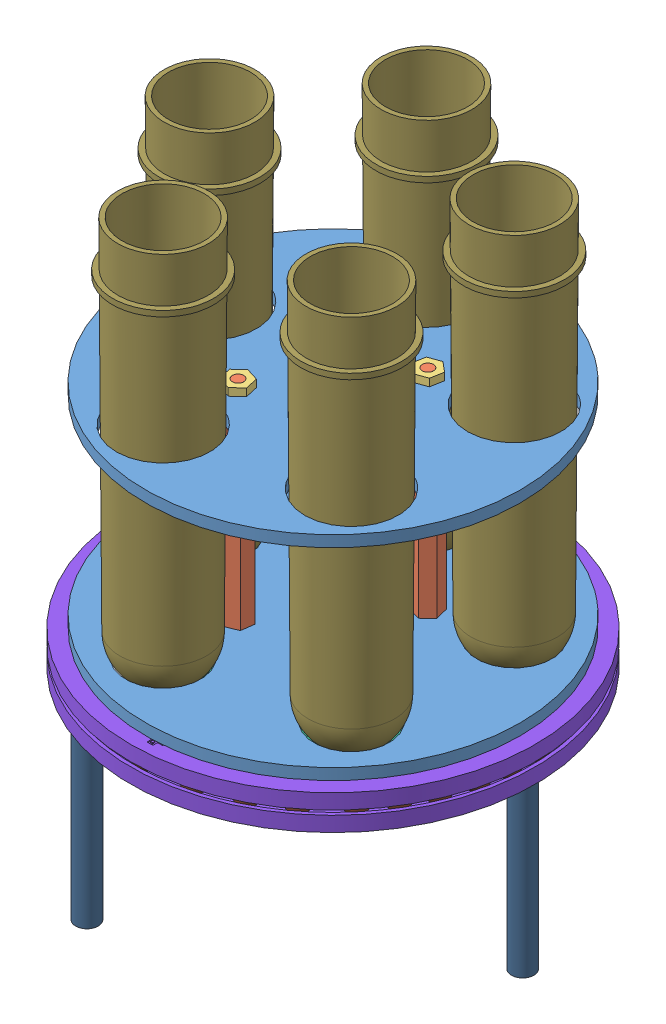
SolidWorks assembly FinalTurntable, configuration Default. Lengths in mm.
Overall size (140.72 159.12 140.72).
63 component instances, 12 part files, 80 mates.
Components (placement in the parent):
- RackTopBottom - Updated-1: RackTopBottom - Updated [Default] at (-230.4539 59.2001 -51.3207) x (-0.633158 0 0.774022) z (0 1 0) size (100 100 56.8)
- Hex Standoff - Updated-1: Hex Standoff - Updated [Default] at (-241.2075 5.7001 -16.3075) x (0.593372 0 -0.804928) z (0 1 0) size (6.07 6.93 56)
- Hex Standoff - Updated-2: Hex Standoff - Updated [Default] at (-234.6976 5.7001 -29.2259) x (0.991066 0 0.133372) z (0 1 0) size (6.07 6.93 56)
- Hex Standoff - Updated-3: Hex Standoff - Updated [Default] at (-210.597 5.7001 -45.9336) x (0.250303 0 -0.968168) z (0 1 0) size (6.07 6.93 56)
- Hex Standoff - Updated-4: Hex Standoff - Updated [Default] at (-265.0629 5.7001 -66.876) x (0.649234 0 0.760589) z (0 1 0) size (6.07 6.93 56)
- M3 Nut Standoff - Updated-1: M3 Nut Standoff - Updated [Default] at (-253.6241 66.7001 -101.6071) x (0.21848 0 0.975841) z (0 -1 0) size (6 6.93 2)
- M3 Nut Standoff - Updated-2: M3 Nut Standoff - Updated [Default] at (-253.226 66.7001 0.9306) x (0.296982 0 -0.954883) z (0 -1 0) size (6 6.93 2)
- M3 Nut Standoff - Updated-3: M3 Nut Standoff - Updated [Default] at (-244.486 66.7001 -34.4131) x (0.64612 0 -0.763236) z (0 -1 0) size (6 6.93 2)
- M3 Nut Standoff - Updated-4: M3 Nut Standoff - Updated [Default] at (-201.2406 66.7001 -76.8592) x (-0.394236 0 0.919009) z (0 -1 0) size (6 6.93 2)
- M3 Standoff Screw - Updated-1: M3 Standoff Screw - Updated [Default] at (-269.8082 0.4001 -37.3883) x (1 0 0) z (0 1 0) size (6 6 11.5)
- BottomPlate-2: BottomPlate [Default] at (-230.4539 2.9001 -51.3207) x (-0.774022 0 -0.633158) z (0 -1 0) size (48 48 1)
- M3 Standoff Screw - Updated-5: M3 Standoff Screw - Updated [Default] at (-244.479 0.4001 -39.9238) x (1 0 0) z (0 1 0) size (6 6 11.5)
- M3 Standoff Screw - Updated-6: M3 Standoff Screw - Updated [Default] at (-270.5567 0.4001 -52.8823) x (0.936079 0 -0.351791) z (0 1 0) size (6 6 11.5)
- M3 Standoff Screw - Updated-7: M3 Standoff Screw - Updated [Default] at (-247.0145 0.4001 -65.2531) x (1 0 0) z (0 1 0) size (6 6 11.5)
- 50T-1: 50T [Default] at (-230.4539 -13.5499 -51.3207) x (-0.99923 0 0.039234) z (0 1 0) size (52 51.94 5.85)
- M4x40 Screw - Updated-2: M4x40 Screw - Updated [Default] at (-230.4539 5.4001 -51.3207) x (0.031411 0 -0.999507) z (0 -1 0) size (7.8 7.8 42.5)
- OuterBearing-1: OuterBearing [Default] at (-230.4539 4.4001 -51.3207) x (0.998722 0 0.050545) z (-0.050545 0 0.998722) size (108 4 108)
- M4 Nut - Updated-4: M4 Nut - Updated [Default] at (-246.9134 -19.2999 -51.8372) x (1 0 -0.000085) z (0 1 0) size (7.12 8.08 3)
- OuterBearing-2: OuterBearing [Default] at (-230.4539 -2.7999 -51.3207) x (-0.031858 0 -0.999492) z (-0.999492 0 0.031858) size (108 4 108)
- Holder-5: Holder [Default] at (-249.9816 -48.7999 -5.2134) size (6 45 6)
- Holder-6: Holder [Default] at (-251.5763 -48.7999 -96.9017) size (6 45 6)
- Holder-7: Holder [Default] at (-180.5025 -48.7999 -51.9772) size (6 45 6)
- Plastic BB-15: Plastic BB [Default] at (-275.5002 13.1962 -61.2014) x (0.215326 -0.491343 0.843929) z (-0.86299 0.308718 0.399927) size (6 6 6)
- Plastic BB-16: Plastic BB [Default] at (-242.8287 -17.2199 -25.7204) size (6 6 6)
- Plastic BB-17: Plastic BB [Default] at (-256.14 -25.7464 43.5967) x (0.678924 0.269881 -0.682808) z (0.333731 0.71493 0.614409) size (6 6 6)
- Plastic BB-18: Plastic BB [Default] at (-247.5088 -17.2229 -19.1254) size (6 6 6)
- Plastic BB-19: Plastic BB [Default] at (-223.1694 -8.2487 -9.1728) x (0.880848 -0.040835 -0.471634) z (0.321981 0.782021 0.53364) size (6 6 6)
- Plastic BB-20: Plastic BB [Default] at (-332.3096 6.3553 -15.6932) x (0.865873 -0.39899 -0.30178) z (0.277856 -0.118075 0.953339) size (6 6 6)
- Plastic BB-21: Plastic BB [Default] at (-272.092 -55.586 -78.0495) x (0.162347 0.858831 -0.485853) z (0.986726 -0.143278 0.076444) size (6 6 6)
- Plastic BB-22: Plastic BB [Default] at (-293.3514 50.1494 -52.6083) x (0.09026 -0.963623 -0.251565) z (0.58268 -0.153756 0.798024) size (6 6 6)
- Plastic BB-23: Plastic BB [Default] at (-239.3384 -17.2401 -32.7624) size (6 6 6)
- Plastic BB-24: Plastic BB [Default] at (-233.1099 -29.6982 -80.7632) x (0.962684 0.242 0.12114) z (-0.073563 -0.196771 0.977686) size (6 6 6)
- Plastic BB-25: Plastic BB [Default] at (-236.9966 -17.2491 -62.344) size (6 6 6)
- Plastic BB-26: Plastic BB [Default] at (-252.809 -17.2534 -88.963) size (6 6 6)
- Plastic BB-27: Plastic BB [Default] at (-220.4475 52.4169 -122.4108) x (0.369836 -0.908472 0.19468) z (-0.706984 -0.411127 -0.575455) size (6 6 6)
- Plastic BB-28: Plastic BB [Default] at (-247.7003 -10.1249 -56.4794) x (0.84441 -0.082528 -0.529302) z (0.492353 0.508909 0.706116) size (6 6 6)
- Plastic BB-29: Plastic BB [Default] at (-235.9603 -17.2443 -55.6713) size (6 6 6)
- Plastic BB-30: Plastic BB [Default] at (-308.099 32.6865 6.1519) x (0.755938 -0.653121 -0.044618) z (0.636947 0.718053 0.280532) size (6 6 6)
- Plastic BB-31: Plastic BB [Default] at (-156.6909 -25.2421 -11.8489) x (-0.812463 0.549497 -0.194826) z (0.443508 0.799428 0.405235) size (6 6 6)
- Plastic BB-32: Plastic BB [Default] at (-252.0729 -24.2451 -53.1086) x (-0.025583 0.257835 0.96585) z (-0.604245 0.765707 -0.220412) size (6 6 6)
- Plastic BB-33: Plastic BB [Default] at (-253.0916 -3.1833 12.282) x (0.921672 -0.229863 -0.312544) z (0.37337 0.306604 0.875551) size (6 6 6)
- Plastic BB-34: Plastic BB [Default] at (-243.3801 -12.867 48.2726) x (0.609745 -0.007805 -0.792559) z (0.616623 0.632933 0.468158) size (6 6 6)
- Plastic BB-35: Plastic BB [Default] at (-229.7792 -39.1049 -66.1656) x (0.86679 0.431125 -0.250614) z (0.208293 0.143611 0.967466) size (6 6 6)
- Plastic BB-36: Plastic BB [Default] at (-233.4906 2.832 -14.1696) x (0.899081 -0.311551 -0.307555) z (0.422142 0.430869 0.797589) size (6 6 6)
- Plastic BB-37: Plastic BB [Default] at (-201.7036 53.4469 -110.7371) x (-0.579141 -0.734052 0.354631) z (0.634275 -0.132442 0.761679) size (6 6 6)
- Plastic BB-38: Plastic BB [Default] at (-333.4327 -9.8102 -21.447) x (0.984185 -0.078607 -0.158748) z (0.175493 0.554722 0.813318) size (6 6 6)
- Plastic BB-39: Plastic BB [Default] at (-233.1878 56.1453 -83.4812) x (-0.297194 -0.952912 -0.060283) z (0.721846 -0.265559 0.639075) size (6 6 6)
- Plastic BB-40: Plastic BB [Default] at (-227.3253 50.3183 -131.584) x (-0.072989 -0.646912 0.759063) z (0.997324 -0.050472 0.052885) size (6 6 6)
- Plastic BB-41: Plastic BB [Default] at (-212.2193 58.5346 -93.915) x (-0.063933 -0.974181 0.216526) z (0.995478 -0.077531 -0.054889) size (6 6 6)
- Plastic BB-42: Plastic BB [Default] at (-243.6939 24.8361 -129.5389) x (-0.681198 -0.243959 0.690256) z (0.285251 0.779885 0.557146) size (6 6 6)
- Plastic BB-43: Plastic BB [Default] at (-327.4625 -11.0441 -27.8578) x (0.870988 -0.102666 -0.480457) z (0.490227 0.246332 0.836061) size (6 6 6)
- Plastic BB-44: Plastic BB [Default] at (-302.7247 -13.2486 -16.1662) x (0.972922 -0.070587 0.220093) z (-0.218423 0.030653 0.975373) size (6 6 6)
- Plastic BB-45: Plastic BB [Default] at (-330.7628 -21.1236 -29.0992) x (0.954445 0.078409 -0.287901) z (0.262205 0.240139 0.934656) size (6 6 6)
- Plastic BB-46: Plastic BB [Default] at (-321.6598 -22.7683 -11.6677) x (0.98991 0.140708 0.016736) z (-0.082434 0.475788 0.875688) size (6 6 6)
- Plastic BB-47: Plastic BB [Default] at (-306.2301 17.5255 -81.6087) x (0.830622 -0.547854 -0.099614) z (0.34971 0.374028 0.858957) size (6 6 6)
- Plastic BB-48: Plastic BB [Default] at (-227.852 -23.7397 -50.0655) x (-0.965187 0.239718 -0.104641) z (-0.112351 -0.741238 -0.661773) size (6 6 6)
- Plastic BB-49: Plastic BB [Default] at (-296.4909 -33.9533 15.134) x (0.571556 0.340695 -0.746492) z (0.671919 0.32787 0.664098) size (6 6 6)
- Plastic BB-50: Plastic BB [Default] at (-269.7873 53.6028 -93.5405) x (0.120309 -0.992302 -0.029353) z (0.208526 -0.003648 0.97801) size (6 6 6)
- TestTube-1: TestTube [Default] at (-201.0065 2.8659 -70.2375) x (-0.772425 0 -0.635106) z (0 1 0) size (27 27 107)
- TestTube-2: TestTube [Default] at (-265.3965 2.7959 -53.3254) x (-0.855611 0 -0.517619) z (0 1 0) size (27 27 107)
- TestTube-3: TestTube [Default] at (-243.1584 3.1689 -18.7078) x (-0.945003 0 -0.327061) z (0 1 0) size (27 27 107)
- TestTube-4: TestTube [Default] at (-203.3632 3.3236 -29.1601) x (-0.627624 0 -0.778516) z (0 1 0) size (27 27 107)
- TestTube-5: TestTube [Default] at (-239.3452 2.8224 -85.1725) x (-0.793467 0 -0.608613) z (0 1 0) size (27 27 107)
Mates (geometry in assembly coordinates):
- Concentric5: concentric aligned: cylinder of RackTopBottom - Updated-1 through (-216.5215 59.2001 -39.9238) axis (0 1 0) radius 1.5; cylinder of Hex Standoff - Updated-2 through (-216.5215 8.2001 -39.9238) axis (0 1 0) radius 1.5
- Coincident2: coincident anti-aligned: plane of RackTopBottom - Updated-1 through (-230.4539 59.2001 -51.3207) normal (0 -1 0); plane of Hex Standoff - Updated-2 through (-216.5215 59.2001 -39.9238) normal (0 1 0)
- Concentric6: concentric aligned: cylinder of RackTopBottom - Updated-1 through (-219.0571 59.2001 -65.2531) axis (0 1 0) radius 1.5; cylinder of Hex Standoff - Updated-3 through (-219.0571 8.2001 -65.2531) axis (0 1 0) radius 1.5
- Coincident3: coincident anti-aligned: plane of RackTopBottom - Updated-1 through (-230.4539 59.2001 -51.3207) normal (0 -1 0); plane of Hex Standoff - Updated-3 through (-219.0571 59.2001 -65.2531) normal (0 1 0)
- Concentric7: concentric aligned: cylinder of RackTopBottom - Updated-1 through (-241.8508 59.2001 -37.3883) axis (0 1 0) radius 1.5; cylinder of Hex Standoff - Updated-1 through (-241.8508 8.2001 -37.3883) axis (0 1 0) radius 1.5
- Coincident4: coincident anti-aligned: plane of RackTopBottom - Updated-1 through (-230.4539 59.2001 -51.3207) normal (0 -1 0); plane of Hex Standoff - Updated-1 through (-241.8508 59.2001 -37.3883) normal (0 1 0)
- Concentric8: concentric aligned: cylinder of RackTopBottom - Updated-1 through (-244.3863 59.2001 -62.7175) axis (0 1 0) radius 1.5; cylinder of Hex Standoff - Updated-4 through (-244.3863 8.2001 -62.7175) axis (0 1 0) radius 1.5
- Coincident5: coincident anti-aligned: plane of RackTopBottom - Updated-1 through (-230.4539 59.2001 -51.3207) normal (0 -1 0); plane of Hex Standoff - Updated-4 through (-244.3863 59.2001 -62.7175) normal (0 1 0)
- Concentric9: concentric anti-aligned: cylinder of Hex Standoff - Updated-4 through (-244.3863 8.2001 -62.7175) axis (0 1 0) radius 1.5; cylinder of M3 Nut Standoff - Updated-1 through (-244.3863 64.2001 -62.7175) axis (0 -1 0) radius 1.5
- Coincident6: coincident anti-aligned: plane of RackTopBottom - Updated-1 through (-230.4539 62.2001 -51.3207) normal (0 1 0); plane of M3 Nut Standoff - Updated-1 through (-244.3863 62.2001 -62.7175) normal (0 -1 0)
- Concentric10: concentric anti-aligned: cylinder of Hex Standoff - Updated-1 through (-241.8508 8.2001 -37.3883) axis (0 1 0) radius 1.5; cylinder of M3 Nut Standoff - Updated-2 through (-241.8508 64.2001 -37.3883) axis (0 -1 0) radius 1.5
- Coincident7: coincident anti-aligned: plane of RackTopBottom - Updated-1 through (-230.4539 62.2001 -51.3207) normal (0 1 0); plane of M3 Nut Standoff - Updated-2 through (-241.8508 62.2001 -37.3883) normal (0 -1 0)
- Concentric11: concentric anti-aligned: cylinder of Hex Standoff - Updated-2 through (-216.5215 8.2001 -39.9238) axis (0 1 0) radius 1.5; cylinder of M3 Nut Standoff - Updated-4 through (-216.5215 64.2001 -39.9238) axis (0 -1 0) radius 1.5
- Coincident8: coincident anti-aligned: plane of RackTopBottom - Updated-1 through (-230.4539 62.2001 -51.3207) normal (0 1 0); plane of M3 Nut Standoff - Updated-4 through (-216.5215 62.2001 -39.9238) normal (0 -1 0)
- Concentric12: concentric anti-aligned: cylinder of Hex Standoff - Updated-3 through (-219.0571 8.2001 -65.2531) axis (0 1 0) radius 1.5; cylinder of M3 Nut Standoff - Updated-3 through (-219.0571 64.2001 -65.2531) axis (0 -1 0) radius 1.5
- Coincident10: coincident anti-aligned: plane of RackTopBottom - Updated-1 through (-230.4539 62.2001 -51.3207) normal (0 1 0); plane of M3 Nut Standoff - Updated-3 through (-219.0571 62.2001 -65.2531) normal (0 -1 0)
- Concentric18: concentric anti-aligned: cylinder of RackTopBottom - Updated-1 through (-241.8508 5.4001 -37.3883) axis (0 1 0) radius 1.5; cylinder of BottomPlate-2 through (-241.8508 2.9001 -37.3883) axis (0 -1 0) radius 1.6
- Concentric19: concentric anti-aligned: cylinder of RackTopBottom - Updated-1 through (-219.0571 5.4001 -65.2531) axis (0 1 0) radius 1.5; cylinder of BottomPlate-2 through (-219.0571 2.9001 -65.2531) axis (0 -1 0) radius 1.6
- Concentric21: concentric anti-aligned: cylinder of BottomPlate-2 through (-244.3863 2.9001 -62.7175) axis (0 -1 0) radius 1.6; cylinder of M3 Standoff Screw - Updated-6 through (-244.3863 0.4001 -62.7175) axis (0 1 0) radius 1.5
- Coincident13: coincident anti-aligned: plane of BottomPlate-2 through (-230.4539 1.9001 -51.3207) normal (0 -1 0); plane of M3 Standoff Screw - Updated-6 through (-244.3863 1.9001 -62.7175) normal (0 1 0)
- Concentric22: concentric anti-aligned: cylinder of BottomPlate-2 through (-219.0571 2.9001 -65.2531) axis (0 -1 0) radius 1.6; cylinder of M3 Standoff Screw - Updated-7 through (-219.0571 0.4001 -65.2531) axis (0 1 0) radius 1.5
- Concentric23: concentric anti-aligned: cylinder of BottomPlate-2 through (-216.5215 2.9001 -39.9238) axis (0 -1 0) radius 1.6; cylinder of M3 Standoff Screw - Updated-5 through (-216.5215 0.4001 -39.9238) axis (0 1 0) radius 1.5
- Concentric24: concentric anti-aligned: cylinder of M3 Standoff Screw - Updated-1 through (-241.8508 0.4001 -37.3883) axis (0 1 0) radius 1.5; cylinder of BottomPlate-2 through (-241.8508 2.9001 -37.3883) axis (0 -1 0) radius 1.6
- Coincident14: coincident anti-aligned: plane of M3 Standoff Screw - Updated-1 through (-241.8508 1.9001 -37.3883) normal (0 1 0); plane of BottomPlate-2 through (-230.4539 1.9001 -51.3207) normal (0 -1 0)
- Coincident15: coincident anti-aligned: plane of BottomPlate-2 through (-230.4539 1.9001 -51.3207) normal (0 -1 0); plane of M3 Standoff Screw - Updated-5 through (-216.5215 1.9001 -39.9238) normal (0 1 0)
- Coincident16: coincident anti-aligned: plane of BottomPlate-2 through (-230.4539 1.9001 -51.3207) normal (0 -1 0); plane of M3 Standoff Screw - Updated-7 through (-219.0571 1.9001 -65.2531) normal (0 1 0)
- Concentric27: concentric aligned: cylinder of BottomPlate-2 through (-230.4539 3.9001 -51.3207) axis (0 -1 0) radius 2.1; cylinder of M4x40 Screw - Updated-2 through (-230.4539 2.9001 -51.3207) axis (0 -1 0) radius 2
- Coincident19: coincident anti-aligned: plane of BottomPlate-2 through (-230.4539 2.9001 -51.3207) normal (0 1 0); plane of M4x40 Screw - Updated-2 through (-230.4539 2.9001 -51.3207) normal (0 -1 0)
- Coincident20: coincident anti-aligned: plane of RackTopBottom - Updated-1 through (-230.4539 5.4001 -51.3207) normal (0 -1 0); plane of M4x40 Screw - Updated-2 through (-230.4539 5.4001 -51.3207) normal (0 1 0)
- Concentric28: concentric anti-aligned: cylinder of 50T-1 through (-230.4539 -13.5499 -51.3207) axis (0 1 0) radius 2; cylinder of M4x40 Screw - Updated-2 through (-230.4539 2.9001 -51.3207) axis (0 -1 0) radius 2
- Concentric29: concentric anti-aligned: cylinder of M4x40 Screw - Updated-2 through (-230.4539 2.9001 -51.3207) axis (0 -1 0) radius 2; cylinder of M4 Nut - Updated-4 through (-230.4539 -16.7999 -51.3207) axis (0 1 0) radius 2
- Coincident22: coincident anti-aligned: plane of 50T-1 through (-230.4539 -13.7999 -51.3207) normal (0 -1 0); plane of M4 Nut - Updated-4 through (-230.4539 -13.7999 -51.3207) normal (0 1 0)
- Concentric31: concentric anti-aligned: cylinder of OuterBearing-1 through (-230.4539 35.1126 -51.3207) axis (0 1 0) radius 46; cylinder of OuterBearing-2 through (-230.4539 -33.5123 -51.3207) axis (0 -1 0) radius 46
- Concentric32: concentric anti-aligned: cylinder of RackTopBottom - Updated-1 through (-230.4539 5.4001 -51.3207) axis (0 1 0) radius 50; cylinder of OuterBearing-2 through (-230.4539 -33.5123 -51.3207) axis (0 -1 0) radius 46
- Coincident26: coincident anti-aligned: plane of RackTopBottom - Updated-1 through (-230.4539 5.4001 -51.3207) normal (0 -1 0); plane of OuterBearing-2 through (-228.7336 5.4001 2.6519) normal (0 1 0)
- Coincident34: coincident anti-aligned: plane of OuterBearing-1 through (-284.3849 -3.7999 -54.0501) normal (0 -1 0); plane of Holder-6 through (-251.5763 -3.7999 -96.9017) normal (0 1 0)
- Coincident36: coincident anti-aligned: plane of OuterBearing-1 through (-284.3849 -3.7999 -54.0501) normal (0 -1 0); plane of Holder-5 through (-249.9816 -3.7999 -5.2134) normal (0 1 0)
- Coincident39: coincident anti-aligned: plane of OuterBearing-1 through (-284.3849 -3.7999 -54.0501) normal (0 -1 0); plane of Holder-5 through (-249.9816 -3.7999 -5.2134) normal (0 1 0)
- Tangent11: tangent anti-aligned: torus of OuterBearing-1; sphere of Plastic BB-32
- Tangent12: tangent anti-aligned: torus of OuterBearing-1; sphere of Plastic BB-34
- Tangent13: tangent anti-aligned: torus of OuterBearing-1; sphere of Plastic BB-30
- Tangent14: tangent anti-aligned: torus of OuterBearing-1; sphere of Plastic BB-31
- Tangent15: tangent anti-aligned: torus of OuterBearing-1; sphere of Plastic BB-33
- Tangent16: tangent anti-aligned: torus of OuterBearing-1; sphere of Plastic BB-15
- Tangent17: tangent anti-aligned: torus of OuterBearing-1; sphere of Plastic BB-18
- Tangent18: tangent anti-aligned: torus of OuterBearing-1; sphere of Plastic BB-16
- Tangent19: tangent anti-aligned: torus of OuterBearing-1; sphere of Plastic BB-17
- Tangent20: tangent anti-aligned: torus of OuterBearing-1; sphere of Plastic BB-23
- Tangent21: tangent anti-aligned: torus of OuterBearing-1; sphere of Plastic BB-19
- Tangent22: tangent anti-aligned: torus of OuterBearing-1; sphere of Plastic BB-29
- Tangent23: tangent anti-aligned: torus of OuterBearing-1; sphere of Plastic BB-25
- Tangent24: tangent anti-aligned: torus of OuterBearing-1; sphere of Plastic BB-26
- Tangent25: tangent anti-aligned: torus of OuterBearing-1; sphere of Plastic BB-27
- Tangent26: tangent anti-aligned: torus of OuterBearing-1; sphere of Plastic BB-28
- Tangent27: tangent anti-aligned: torus of OuterBearing-1; sphere of Plastic BB-22
- Tangent28: tangent anti-aligned: torus of OuterBearing-1; sphere of Plastic BB-20
- Tangent29: tangent anti-aligned: torus of OuterBearing-1; sphere of Plastic BB-21
- Tangent30: tangent anti-aligned: torus of OuterBearing-1; sphere of Plastic BB-24
- Tangent31: tangent anti-aligned: torus of OuterBearing-1; sphere of Plastic BB-35
- Tangent32: tangent anti-aligned: torus of OuterBearing-1; sphere of Plastic BB-36
- Tangent33: tangent anti-aligned: torus of OuterBearing-1; sphere of Plastic BB-43
- Tangent34: tangent anti-aligned: torus of OuterBearing-1; sphere of Plastic BB-37
- Tangent35: tangent anti-aligned: torus of OuterBearing-1; sphere of Plastic BB-45
- Tangent36: tangent anti-aligned: torus of OuterBearing-1; sphere of Plastic BB-44
- Tangent38: tangent anti-aligned: torus of OuterBearing-1; sphere of Plastic BB-46
- Tangent39: tangent anti-aligned: torus of OuterBearing-1; sphere of Plastic BB-38
- Tangent40: tangent anti-aligned: torus of OuterBearing-1; sphere of Plastic BB-39
- Tangent41: tangent anti-aligned: torus of OuterBearing-1; sphere of Plastic BB-47
- Tangent42: tangent anti-aligned: torus of OuterBearing-1; sphere of Plastic BB-48
- Tangent43: tangent anti-aligned: torus of OuterBearing-1; sphere of Plastic BB-49
- Tangent44: tangent anti-aligned: torus of OuterBearing-1; sphere of Plastic BB-50
- Tangent45: tangent anti-aligned: torus of OuterBearing-1; sphere of Plastic BB-40
- Tangent46: tangent anti-aligned: torus of OuterBearing-1; sphere of Plastic BB-41
- Tangent47: tangent anti-aligned: torus of OuterBearing-1; sphere of Plastic BB-42
- Distance4: distance = 1.2 mm anti-aligned: plane of OuterBearing-2 through (-228.7642 1.4001 1.6938) normal (0 -1 0); plane of OuterBearing-1 through (-283.4275 0.2001 -54.0016) normal (0 1 0)
- Concentric45: concentric anti-aligned: cylinder of RackTopBottom - Updated-1 through (-201.0065 59.2001 -70.2375) axis (0 1 0) radius 12.5; cone of TestTube-1 through (-201.0065 56.3659 -70.2375) axis (0 -1 0)
- Concentric46: concentric anti-aligned: cylinder of RackTopBottom - Updated-1 through (-239.3452 59.2001 -85.1725) axis (0 1 0) radius 12.5; cone of TestTube-5 through (-239.3452 56.3224 -85.1725) axis (0 -1 0)
- Concentric47: concentric anti-aligned: cylinder of RackTopBottom - Updated-1 through (-265.3965 59.2001 -53.3254) axis (0 1 0) radius 12.5; cone of TestTube-2 through (-265.3965 56.2959 -53.3254) axis (0 -1 0)
- Concentric48: concentric anti-aligned: cylinder of RackTopBottom - Updated-1 through (-243.1584 59.2001 -18.7078) axis (0 1 0) radius 12.5; cone of TestTube-3 through (-243.1584 56.6689 -18.7078) axis (0 -1 0)
- Concentric49: concentric anti-aligned: cylinder of RackTopBottom - Updated-1 through (-203.3632 59.2001 -29.1601) axis (0 1 0) radius 12.5; cone of TestTube-4 through (-203.3632 56.8236 -29.1601) axis (0 -1 0)
